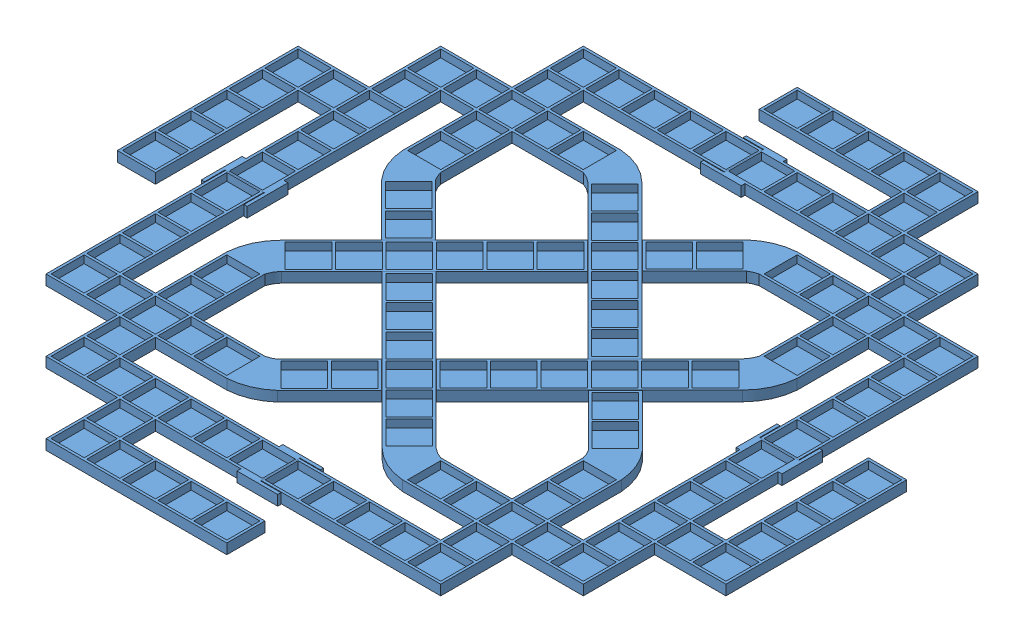
SolidWorks assembly plateau, configuration Défaut. Lengths in mm.
Overall size (267 4 267).
4 component instances, 1 part files, 7 mates.
Components (placement in the parent):
- quart_plateau-1: quart_plateau [Défaut] at (-8.1661 -6.2152 162.6542) size (174.28 4 173.83)
- quart_plateau-2: quart_plateau [Défaut] at (-107.5144 -6.2152 213.0418) x (0 0 -1) z (1 0 0) size (174.28 4 173.83)
- quart_plateau-3: quart_plateau [Défaut] at (-57.1267 -6.2152 312.3902) x (-1 0 0) z (0 0 -1) size (174.28 4 173.83)
- quart_plateau-4: quart_plateau [Défaut] at (42.2216 -6.2152 262.0025) x (0 0 1) z (-1 0 0) size (174.28 4 173.83)
Mates (geometry in assembly coordinates):
- Coïncidente2: coincident aligned: plane of quart_plateau-1 through (-57.6635 -6.2152 212.1517) normal (0 -1 0); plane of quart_plateau-2 through (-58.0169 -6.2152 262.5393) normal (0 -1 0)
- Coïncidente5: coincident aligned: plane of quart_plateau-2 through (-58.0169 -6.2152 262.5393) normal (0 -1 0); plane of quart_plateau-3 through (-7.6293 -6.2152 262.8927) normal (0 -1 0)
- Coïncidente12: coincident aligned: plane of quart_plateau-1 through (-57.6635 -6.2152 212.1517) normal (0 -1 0); plane of quart_plateau-4 through (-7.2759 -6.2152 212.505) normal (0 -1 0)
- Coïncidente14: coincident anti-aligned: plane of quart_plateau-1 through (-39.6464 -6.2152 162.6542) normal (-1 0 0); plane of quart_plateau-2 through (-39.6464 -6.2152 213.0418) normal (1 0 0)
- Coïncidente15: coincident anti-aligned: plane of quart_plateau-1 through (-8.1661 -6.2152 230.5222) normal (0 0 1); plane of quart_plateau-4 through (42.2216 -6.2152 230.5222) normal (0 0 -1)
- Coïncidente16: coincident anti-aligned: plane of quart_plateau-3 through (-25.6464 -6.2152 312.3902) normal (1 0 0); plane of quart_plateau-4 through (-25.6464 -6.2152 262.0025) normal (-1 0 0)
- Coïncidente17: coincident anti-aligned: plane of quart_plateau-2 through (-107.5144 -6.2152 244.5222) normal (0 0 1); plane of quart_plateau-3 through (-57.1267 -6.2152 244.5222) normal (0 0 -1)
